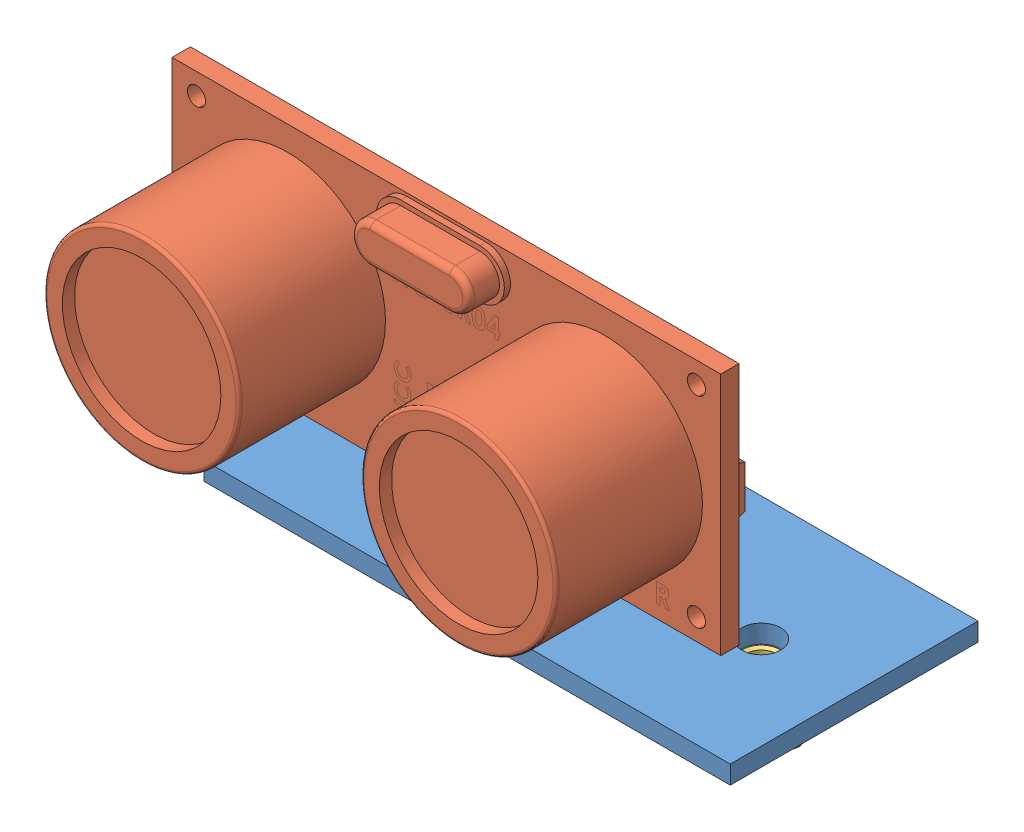
SolidWorks assembly 01.01.03.00_Ultrasonic_with_mount, configuration Default. Lengths in mm.
Overall size (45 35.3 34.01).
6 component instances, 3 part files, 17 mates.
Components (placement in the parent):
- 01.01.03.01_Ultrasonic_Vero-1: 01.01.03.01_Ultrasonic_Vero [Default] at origin size (43.18 10.5 20.32)
- Ultrasonic-HCSR04-1: Ultrasonic-HCSR04 [Default] at (21.59 20.5 0.19) size (45 26.6 18)
- hexagon nut style 1 (grades a and b) as-2: hexagon nut style 1 (grades a and b) as [AS 1112.1 S1 - M3-D-N] at (35.56 0 -10.16) x (0.865385 0 0.501108) z (0 1 0) size (5.5 6.35 2.4)
- hexagon nut style 1 (grades a and b) as-5: hexagon nut style 1 (grades a and b) as [AS 1112.1 S1 - M3-D-N] at (35.56 -2.4 -10.16) x (0.865385 0 0.501108) z (0 1 0) size (5.5 6.35 2.4)
- hexagon nut style 1 (grades a and b) as-6: hexagon nut style 1 (grades a and b) as [AS 1112.1 S1 - M3-D-N] at (7.62 0 -10.16) x (-0.001279 0 0.999999) z (0 1 0) size (5.5 6.35 2.4)
- hexagon nut style 1 (grades a and b) as-7: hexagon nut style 1 (grades a and b) as [AS 1112.1 S1 - M3-D-N] at (7.62 -2.4 -10.16) x (-0.001279 0 0.999999) z (0 1 0) size (5.5 6.35 2.4)
Mates (geometry in assembly coordinates):
- Coincident1: coincident aligned: plane of 01.01.03.01_Ultrasonic_Vero-1 through (0 0 0) normal (1 0 0)
- Coincident2: coincident aligned: plane of 01.01.03.01_Ultrasonic_Vero-1 through (0 0 0) normal (0 1 0)
- Coincident3: coincident aligned: plane of 01.01.03.01_Ultrasonic_Vero-1 through (0 0 0) normal (0 0 1)
- Coincident4: coincident anti-aligned: plane of 01.01.03.01_Ultrasonic_Vero-1 through (0 10.5 0) normal (0 1 0); plane of Ultrasonic-HCSR04-1 through (44.09 10.5 1.69) normal (0 -1 0)
- Coincident5: coincident: plane of 01.01.03.01_Ultrasonic_Vero-1 through (21.59 0 0) normal (1 0 0); line of Ultrasonic-HCSR04-1 through (21.59 13.04 0.19) axis (0 0 -1)
- Coincident6: coincident: plane of 01.01.03.01_Ultrasonic_Vero-1 through (0 0 -3.81) normal (0 0 -1); line of Ultrasonic-HCSR04-1 through (25.74 12.6991 -3.81) axis (-1 0 0)
- Concentric1: concentric anti-aligned: cylinder of 01.01.03.01_Ultrasonic_Vero-1 through (35.56 1.5 -10.16) axis (0 -1 0) radius 1.6; cylinder of hexagon nut style 1 (grades a and b) as-2 through (35.56 -2.4 -10.16) axis (0 1 0) radius 1.25
- Coincident7: coincident anti-aligned: plane of 01.01.03.01_Ultrasonic_Vero-1 through (0 0 0) normal (0 -1 0); plane of hexagon nut style 1 (grades a and b) as-2 through (37.1512 0 -12.908) normal (0 1 0)
- Coincident8: coincident anti-aligned: plane of hexagon nut style 1 (grades a and b) as-2 through (37.1512 -2.4 -12.908) normal (0 -1 0); plane of hexagon nut style 1 (grades a and b) as-5 through (37.1512 -2.4 -12.908) normal (0 1 0)
- Concentric2: concentric aligned: cylinder of hexagon nut style 1 (grades a and b) as-2 through (35.56 -2.4 -10.16) axis (0 1 0) radius 1.25; cylinder of hexagon nut style 1 (grades a and b) as-5 through (35.56 -4.8 -10.16) axis (0 1 0) radius 1.25
- Parallel1: parallel aligned: plane of hexagon nut style 1 (grades a and b) as-2 through (38.7354 -2.4 -10.1559) normal (0.866664 0 -0.498892); plane of hexagon nut style 1 (grades a and b) as-5 through (38.7354 -4.8 -10.1559) normal (0.866664 0 -0.498892)
- Concentric3: concentric aligned: cylinder of hexagon nut style 1 (grades a and b) as-6 through (7.62 -2.4 -10.16) axis (0 1 0) radius 1.25; cylinder of hexagon nut style 1 (grades a and b) as-7 through (7.62 -4.8 -10.16) axis (0 1 0) radius 1.25
- Parallel2: parallel aligned: plane of hexagon nut style 1 (grades a and b) as-6 through (10.7954 -2.4 -10.1559) normal (0.866664 0 -0.498892); plane of hexagon nut style 1 (grades a and b) as-7 through (10.7954 -4.8 -10.1559) normal (0.866664 0 -0.498892)
- Concentric4: concentric anti-aligned: cylinder of 01.01.03.01_Ultrasonic_Vero-1 through (7.62 1.5 -10.16) axis (0 -1 0) radius 1.6; cylinder of hexagon nut style 1 (grades a and b) as-6 through (7.62 -2.4 -10.16) axis (0 1 0) radius 1.25
- Coincident9: coincident anti-aligned: plane of 01.01.03.01_Ultrasonic_Vero-1 through (0 0 0) normal (0 -1 0); plane of hexagon nut style 1 (grades a and b) as-6 through (10.7954 0 -10.1559) normal (0 1 0)
- Coincident10: coincident anti-aligned: plane of hexagon nut style 1 (grades a and b) as-6 through (10.7954 -2.4 -10.1559) normal (0 -1 0); plane of hexagon nut style 1 (grades a and b) as-7 through (10.7954 -2.4 -10.1559) normal (0 1 0)
- Parallel3: parallel aligned: plane of hexagon nut style 1 (grades a and b) as-2 through (37.1512 -2.4 -12.908) normal (0.001279 0 -0.999999); plane of hexagon nut style 1 (grades a and b) as-6 through (9.2112 -2.4 -12.908) normal (0.001279 0 -0.999999)
